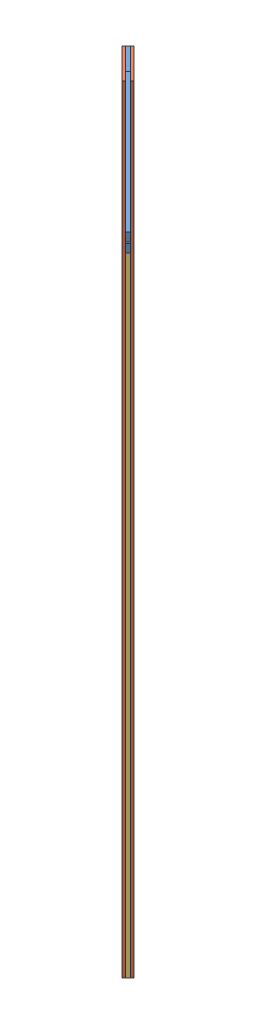
SolidWorks assembly Assem1, configuration Default. Lengths in mm.
Overall size (202.94 910 202.94).
4 component instances, 3 part files, 13 mates.
Components (placement in the parent):
- carbon fin-1: carbon fin [Default] at (11.3354 -22.093 132.0694) x (0.707107 0 0.707107) z (-0.707107 0 0.707107) size (280 80 4)
- kojas 2mm-1: kojas 2mm [Default] at (-75.1946 -442.279 41.2967) x (0.707107 0 0.707107) z (-0.707107 0 0.707107) size (50 900 3)
- kojas 4mm-1: kojas 4mm [Default] at (-77.3159 -512.279 43.418) x (0.707107 0 0.707107) z (-0.707107 0 0.707107) size (50 830 4)
- kojas 2mm-2: kojas 2mm [Default] at (-80.1444 -442.279 46.2465) x (0.707107 0 0.707107) z (-0.707107 0 0.707107) size (50 900 3)
Mates (geometry in assembly coordinates):
- Coincident4: coincident: plane of assembly; plane of assembly; plane of carbon fin-1 through (-62.2037 18 64.1871) normal (-0.707107 0 -0.707107); plane of kojas 2mm-1 through (-59.3752 -892 61.3587) normal (0.707107 0 0.707107)
- Coincident5: coincident: plane of assembly; plane of assembly; plane of carbon fin-1 through (11.3354 -22.093 132.0694) normal (0.707107 0 -0.707107); plane of kojas 2mm-1 through (-77.3159 -442.279 43.418) normal (-0.707107 0 0.707107)
- Coincident6: coincident: plane of assembly; plane of assembly; plane of carbon fin-1 through (-83.4169 -62 42.9739) normal (0 -1 0); plane of kojas 4mm-1 through (-62.2037 -62 64.1871) normal (0 1 0)
- Coincident9: coincident: plane of assembly; plane of assembly; plane of kojas 2mm-1 through (-94.7306 8 26.0034) normal (-0.707107 0 -0.707107); plane of kojas 4mm-1 through (-97.559 -62 28.8318) normal (-0.707107 0 -0.707107)
- Coincident10: coincident: plane of assembly; plane of assembly; plane of kojas 2mm-1 through (-77.3159 -442.279 43.418) normal (-0.707107 0 0.707107); plane of kojas 4mm-1 through (-77.3159 -512.279 43.418) normal (0.707107 0 -0.707107)
- Coincident11: coincident: plane of assembly; plane of assembly; plane of kojas 4mm-1 through (-80.1444 -512.279 46.2465) normal (-0.707107 0 0.707107); plane of kojas 2mm-2 through (-80.1444 -442.279 46.2465) normal (0.707107 0 -0.707107)
- Coincident12: coincident: plane of assembly; plane of assembly; plane of kojas 4mm-1 through (-97.559 -62 28.8318) normal (-0.707107 0 -0.707107); plane of kojas 2mm-2 through (-99.6803 8 30.9531) normal (-0.707107 0 -0.707107)
- Coincident13: coincident: plane of assembly; plane of assembly; plane of carbon fin-1 through (72.1631 8 71.2418) normal (0 1 0); plane of kojas 2mm-2 through (-64.325 8 66.3085) normal (0 1 0)
- Coincident14: coincident: plane of assembly; plane of assembly; plane of carbon fin-1 through (72.1631 8 71.2418) normal (0 1 0); plane of kojas 2mm-1 through (-59.3752 8 61.3587) normal (0 1 0)
- Coincident15: coincident: plane of ? through (-223.424 0 -99.7686) normal (0 -1 0); plane of assembly through (0 0 0) normal (0 1 0)
- Coincident16: coincident: plane of kojas 2mm-2 through (-82.2657 -442.279 48.3678) normal (-0.707107 0 0.707107); plane of ? through (-99.6803 0 30.9531) normal (0.707107 0 -0.707107)
- Coincident17: coincident: plane of carbon fin-1 through (72.1631 8 71.2418) normal (0 1 0); plane of ? through (-223.424 8 -99.7686) normal (0 1 0)
- Coincident18: coincident: plane of carbon fin-1 through (-33.903 -22.093 -34.8242) normal (-0.707107 0 -0.707107); plane of ? through (-92.6093 0 23.8821) normal (0.707107 0 0.707107)
